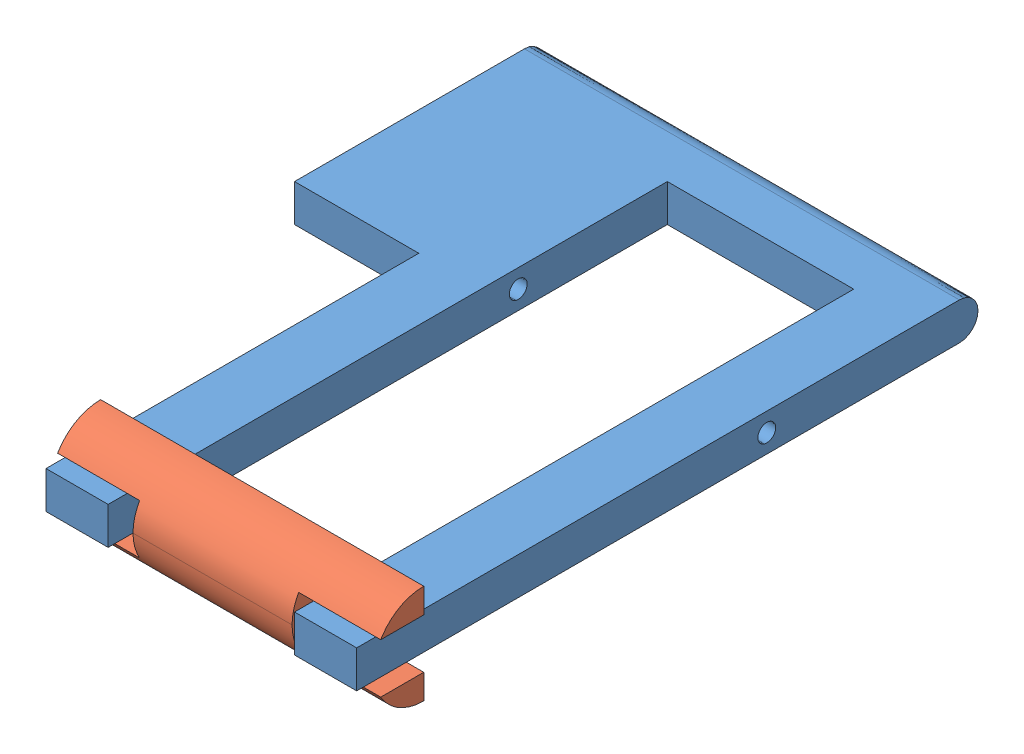
SolidWorks assembly frame, configuration Default. Lengths in mm.
Overall size (17.7 4 25).
2 component instances, 2 part files, 3 mates.
Components (placement in the parent):
- fork-1: fork [Default] at (2.4865 16.7152 20.3093) x (1 0 0) z (0 1 0) size (17.5 25 1.5)
- slider-1: slider [Default] at (7.1865 15.2152 32.8093) size (13 4 2)
Mates (geometry in assembly coordinates):
- Coincident1: coincident anti-aligned: plane of fork-1 through (2.4865 18.2152 20.3093) normal (0 1 0); plane of slider-1 through (16.8865 18.2152 34.8093) normal (0 -1 0)
- Distance2: distance = 0.6 mm anti-aligned: plane of fork-1 through (17.4865 18.2152 35.3093) normal (-1 0 0); plane of slider-1 through (16.8865 16.2152 34.8093) normal (1 0 0)
- LimitDistance1: limit distance = 20 mm anti-aligned: plane of fork-1 through (17.4865 18.2152 12.8093) normal (0 0 1); plane of slider-1 through (7.1865 15.2152 32.8093) normal (0 0 -1)
